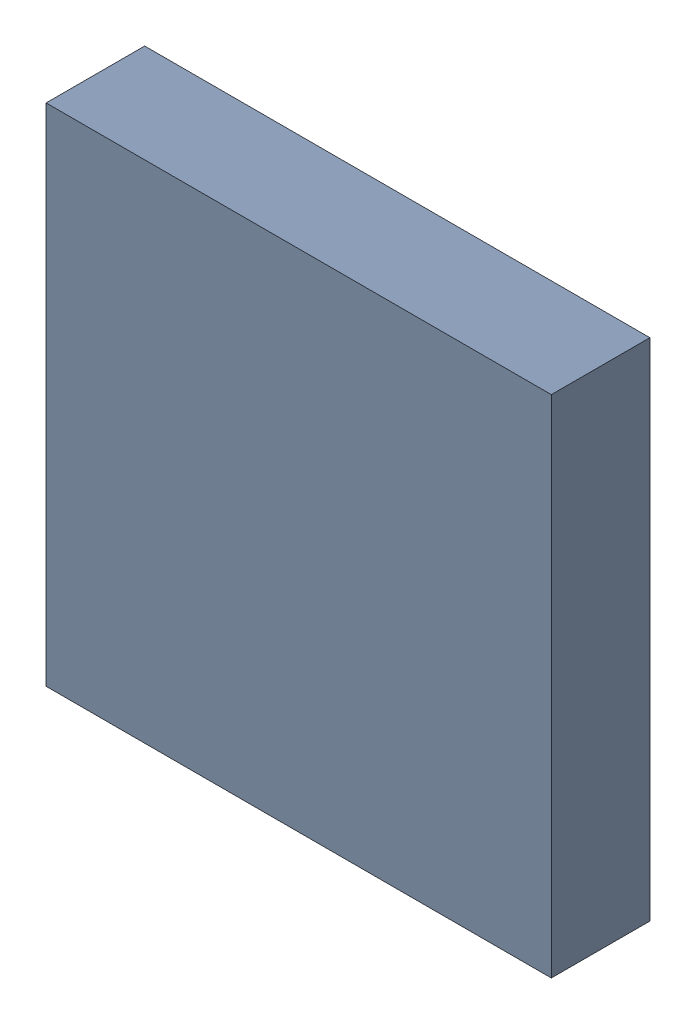
SolidWorks assembly U401PCB, configuration Default. Lengths in mm.
Overall size (4.1 4.1 0.8).
2 component instances, 1 part files, 0 mates.
Components (placement in the parent):
- 846486552-1: 846486552 [Default] at (84.69 85.6 0) size (4.1 4.1 0.8)
  - Extruded_23-1: Extruded_23 [Default] at origin size (4.1 4.1 0.8)
